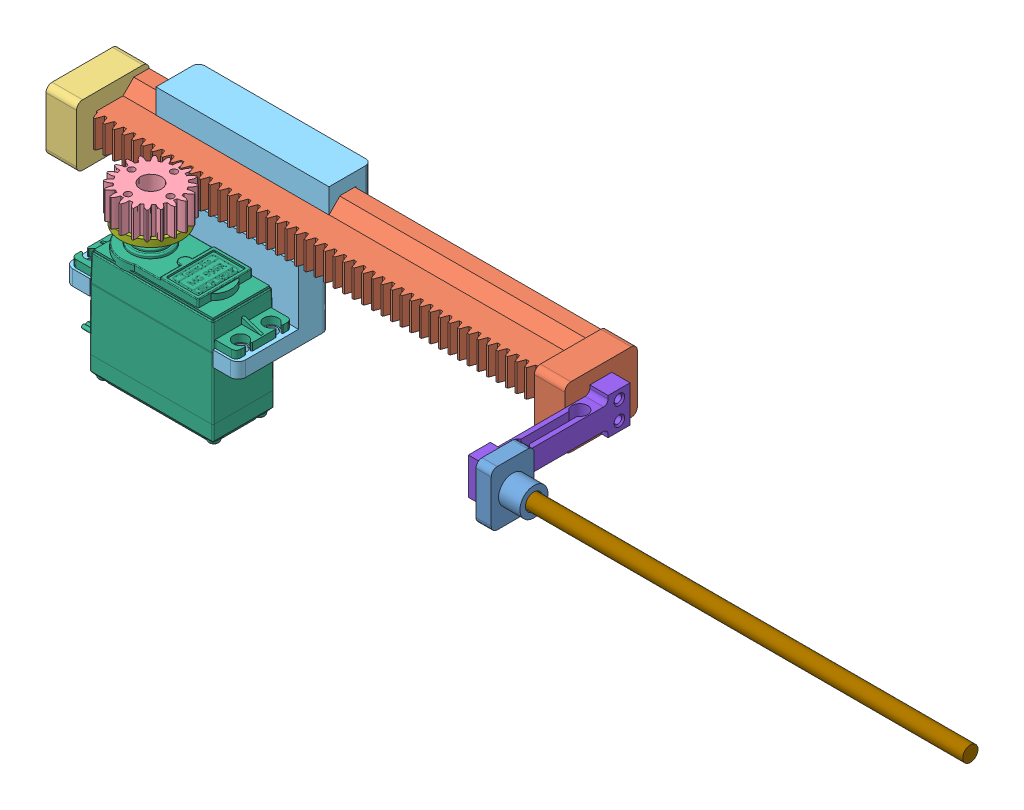
SolidWorks assembly Actuador lineal con sensor, configuration Predeterminado. Lengths in mm.
Overall size (331 63.95 64.21).
9 component instances, 9 part files, 24 mates.
Components (placement in the parent):
- Acople sensor V2-1: Acople sensor V2 [Predeterminado] at (138.7234 32.973 23.3069) x (0 0 1) z (0 -1 0) size (14 18 18)
- Cremallera 1-1: Cremallera 1 [Predeterminado] at (-39.2766 28.473 -20.0414) x (1 0 0) z (0 -1 0) size (160 23.77 20)
- Cremallera 2-1: Cremallera 2 [Predeterminado] at (-39.2766 28.473 -20.0414) x (1 0 0) z (0 -1 0) size (10 23.77 20)
- Piñón V5-1: Piñón V5 [DIN - Spur gear 1M 20T 20PA 5FW ---S20A75H50L8N] at (-10.08 37.4 0) x (0 -1 0) z (0.99646 0 0.084062) size (9 21.8 21.8)
- Soporte servo V4-1: Soporte servo V4 [Predeterminado] at (0 5.1 0) x (1 0 0) z (0 1 0) size (56.7 43.8 40.45)
- Tower Pro MG 996R Servomotor-1: Tower Pro MG 996R Servomotor [Default] at origin size (57.9 44.5 20)
- Servo Horns-1: Servo Horns [Circular Horn] at (-10.08 27.25 0) x (-0.99646 0 -0.084062) z (-0.084062 0 0.99646) size (20 5.5 20)
- 100g_load_cell-1: 100g_load_cell [Default] at (123.7234 32.973 3.3069) x (0 0 1) z (0 1 0) size (47 6 12)
- Palo-1: Palo [Predeterminado] at (131.7234 32.973 23.3069) x (0 0.293185 -0.956056) z (0 -0.956056 -0.293185) size (5 150 5)
Mates (geometry in assembly coordinates):
- Concentric1: concentric anti-aligned: cylinder of Piñón V5-1 through (-10.08 -12.6001 0) axis (0 1 0) radius 3.5; circle of Tower Pro MG 996R Servomotor-1
- Coincident1: coordinate: point of Tower Pro MG 996R Servomotor-1
- Concentric2: concentric anti-aligned: circle of Tower Pro MG 996R Servomotor-1; cylinder of Servo Horns-1 through (-10.08 22.9 0) axis (0 1 0) radius 4.4
- Coincident2: coincident anti-aligned: plane of Tower Pro MG 996R Servomotor-1 through (-10.08 26.1 0) normal (0 1 0); plane of Servo Horns-1 through (-10.08 26.1 0) normal (0 -1 0)
- Concentric3: concentric anti-aligned: cylinder of Piñón V5-1 through (-3.1048 37.4 0.5884) axis (0 -1 0) radius 1.1; cylinder of Servo Horns-1 through (-3.1048 26.1 0.5884) axis (0 1 0) radius 0.75
- Concentric4: concentric anti-aligned: circle of Piñón V5-1; cylinder of Servo Horns-1 through (-17.0552 26.1 -0.5884) axis (0 1 0) radius 0.75
- Coincident3: coincident anti-aligned: plane of Piñón V5-1 through (-10.08 28.4 0) normal (0 -1 0); plane of Servo Horns-1 through (-10.08 28.4 0) normal (0 1 0)
- Concentric5: concentric anti-aligned: cylinder of Soporte servo V4-1 through (-24.25 10.1 5) axis (0 -1 0) radius 2; cylinder of Tower Pro MG 996R Servomotor-1 through (-24.25 -18.4 5) axis (0 1 0) radius 2.375
- Concentric6: concentric anti-aligned: cylinder of Soporte servo V4-1 through (24.25 10.1 5) axis (0 -1 0) radius 2; cylinder of Tower Pro MG 996R Servomotor-1 through (24.25 -18.4 5) axis (0 1 0) radius 2.375
- Coincident4: coincident anti-aligned: plane of Soporte servo V4-1 through (0 10.1 0) normal (0 1 0); plane of Tower Pro MG 996R Servomotor-1 through (0 10.1 0) normal (0 -1 0)
- Width2: width anti-aligned: plane of Soporte servo V4-1 through (-57.1307 41.223 -28.777) normal (0 -1 0); plane of Cremallera 1-1 through (-57.1307 24.723 -23.577) normal (0 1 0); plane of Soporte servo V4-1 through (-39.2766 41.0086 -23.577) normal (0 1 0); plane of Cremallera 1-1 through (-39.2766 24.9375 -23.577) normal (0 -1 0)
- Distance1: distance = 0.2 mm anti-aligned: plane of Cremallera 1-1 through (-39.2766 41.0086 -28.577) normal (0 0 -1); plane of Soporte servo V4-1 through (-57.1307 24.723 -28.777) normal (0 0 1)
- Coincident6: coincident anti-aligned: plane of Cremallera 1-1 through (-39.2766 37.473 -20.0414) normal (-1 0 0); plane of Cremallera 2-1 through (-39.2766 28.473 -20.0414) normal (1 0 0)
- Coincident7: coincident aligned: plane of Cremallera 1-1 through (-39.2766 41.0086 -28.577) normal (0 0 -1); plane of Cremallera 2-1 through (-39.2766 41.0086 -28.577) normal (0 0 -1)
- Width3: width aligned: plane of Cremallera 2-1 through (-49.2766 42.973 -26.577) normal (0 1 0); plane of Cremallera 1-1 through (-49.2766 22.973 -26.577) normal (0 -1 0); plane of Cremallera 2-1 through (-39.2766 41.0086 -23.577) normal (0 1 0); plane of Cremallera 1-1 through (-39.2766 24.9375 -23.577) normal (0 -1 0)
- RackPinionMate1: rack pinion = 17.498 mm: line of Cremallera 1-1 through (37.9999 37.473 -9.0414) axis (0.34202 0 -0.939693); circle of Piñón V5-1
- Concentric7: concentric aligned: cylinder of Cremallera 1-1 through (106.1979 29.973 -16.6931) axis (1 0 0) radius 1.6; cylinder of 100g_load_cell-1 through (126.7234 29.973 -16.6931) axis (1 0 0) radius 1.25
- Concentric8: concentric aligned: cylinder of Cremallera 1-1 through (106.1979 35.973 -16.6931) axis (1 0 0) radius 1.6; cylinder of 100g_load_cell-1 through (126.7234 35.973 -16.6931) axis (1 0 0) radius 1.25
- Coincident8: coincident anti-aligned: plane of Cremallera 1-1 through (120.7234 24.973 -6.8092) normal (1 0 0); plane of 100g_load_cell-1 through (120.7234 27.973 18.1069) normal (-1 0 0)
- Concentric9: concentric anti-aligned: circle of Acople sensor V2-1; cylinder of 100g_load_cell-1 through (126.7234 35.973 23.3069) axis (1 0 0) radius 1.25
- Concentric10: concentric aligned: cylinder of Acople sensor V2-1 through (120.7234 29.973 23.3069) axis (1 0 0) radius 1.55; cylinder of 100g_load_cell-1 through (126.7234 29.973 23.3069) axis (1 0 0) radius 1.25
- Coincident9: coincident anti-aligned: plane of Acople sensor V2-1 through (126.7234 32.973 23.3069) normal (-1 0 0); plane of 100g_load_cell-1 through (126.7234 27.973 18.1069) normal (1 0 0)
- Concentric11: concentric anti-aligned: cylinder of Acople sensor V2-1 through (131.7234 32.973 23.3069) axis (1 0 0) radius 2.8; cylinder of Palo-1 through (281.7234 32.973 23.3069) axis (-1 0 0) radius 2.5
- Coincident10: coincident anti-aligned: plane of Acople sensor V2-1 through (131.7234 32.973 23.3069) normal (1 0 0); plane of Palo-1 through (131.7234 32.973 23.3069) normal (-1 0 0)
